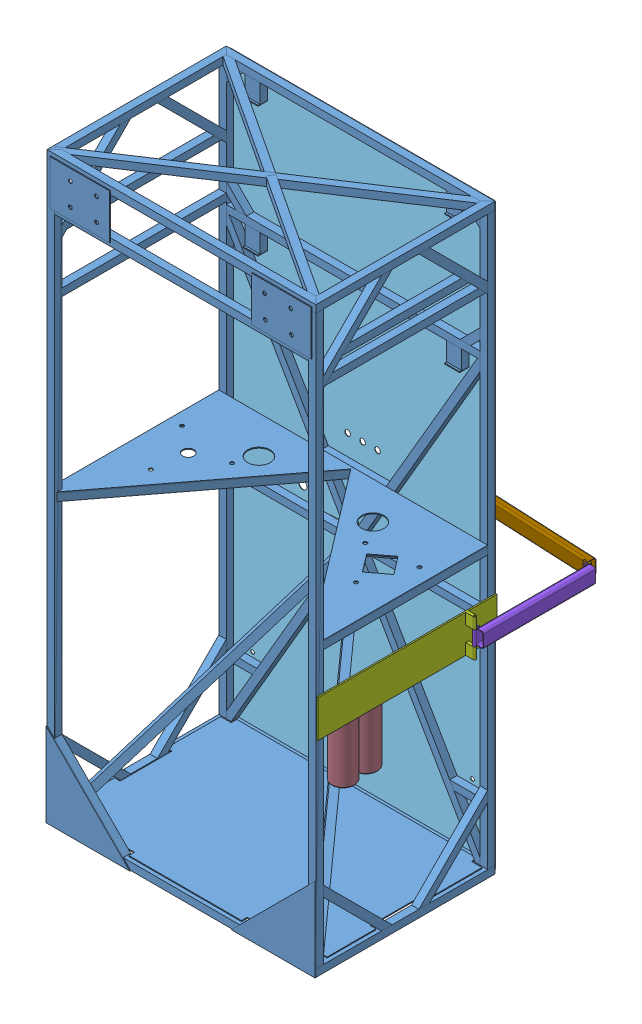
SolidWorks assembly Main Assembly, configuration Default. Lengths in mm.
Overall size (1333.5 2172.1 1083.06).
21 component instances, 13 part files, 25 mates.
Components (placement in the parent):
- test stand-1: test stand [Default<As Machined>] at origin size (1333.5 2172.1 876.3)
- Load cell and motor mount assembly final-1: Load cell and motor mount assembly final [Default] at (-8.9586 768.35 -389.2086) x (-1 0 0) z (0 -1 0) size (205.76 59.05 205.76)
  - Engine and Load Cell Mounting Plate3-1: Engine and Load Cell Mounting Plate3 [Default] at origin size (186.69 31.75 186.69)
  - Load Cell7-4: Load Cell7 [Default] at (0 -20.955 87.6411) x (0 0 -1) z (1 0 0) size (30.48 38.1 12.7)
  - load cell pin-2: load cell pin [Default] at (12.065 -7.62 77.4811) x (0 1 0) z (0 0 1) size (9.21 32.32 9.21)
  - load cell pin-5: load cell pin [Default] at (77.4811 -7.62 -12.065) x (0 1 0) z (1 0 0) size (9.21 32.32 9.21)
  - load cell pin-6: load cell pin [Default] at (-12.065 -7.62 -77.4811) x (0 1 0) z (0 0 -1) size (9.21 32.32 9.21)
  - load cell pin-7: load cell pin [Default] at (-77.4811 -7.62 12.065) x (0 1 0) z (-1 0 0) size (9.21 32.32 9.21)
  - Load Cell7-5: Load Cell7 [Default] at (87.6411 -20.955 0) x (-1 0 0) z (0 0 -1) size (30.48 38.1 12.7)
  - Load Cell7-6: Load Cell7 [Default] at (0 -20.955 -87.6411) x (0 0 1) z (-1 0 0) size (30.48 38.1 12.7)
  - Load Cell7-7: Load Cell7 [Default] at (-87.6411 -20.955 0) size (30.48 38.1 12.7)
- Blast Shield-1: Blast Shield [Default] at (6.35 996.95 -304.8) x (-1 0 0) z (0 0 -1) size (901.7 1968.5 1.59)
- Nozzle_Manifold-1: Nozzle_Manifold [Default] at (-8.9586 768.35 -549.5767) x (0.976633 0.214916 0) z (-0.214916 0.976633 0) size (138.44 174.52 138.44)
- Igniter Hinge Plate-1: Igniter Hinge Plate [Default] at (461.9625 762 -1.5875) x (0 0 1) z (-1 0 0) size (609.6 127 34.92)
- Igniter Arm 1st Section-1: Igniter Arm 1st Section [Default] at (500.0625 762 -400.05) x (0 1 0) z (0 0 -1) size (101.6 30.16 400.05)
- Igniter Arm 2nd Section-1: Igniter Arm 2nd Section [Default] at (267.5408 762 -618.3698) x (0 1 0) z (-0.998895 0 -0.047001) size (50.8 30.16 441.32)
- Igniter Torch-1: Igniter Torch [Default] at (-2.6983 761.9789 -554.7283) x (-0.086802 0.024341 -0.995928) z (0.179155 0.983785 0.00843) size (151.95 26.31 21.84)
- Igniter Torch Attatchment Bracket-1: Igniter Torch Attatchment Bracket [Default] at (5.3734 762 -619.6442) x (0.047001 0 -0.998895) z (0.998895 0 0.047001) size (12.7 38.1 71.44)
- Igniter Torch Attatchment Bracket Clamp-1: Igniter Torch Attatchment Bracket Clamp [Default] at (-4.8698 762 -620.1262) x (0.047001 0 -0.998895) z (0.998895 0 0.047001) size (12.7 38.1 15.88)
- FuelOxy Bottle-1: FuelOxy Bottle [Default] at (418.864 501.4728 95.8553) size (76.2 269.24 76.2)
- FuelOxy Bottle-2: FuelOxy Bottle [Default] at (418.3385 498.7814 173.287) size (76.2 269.24 76.2)
Mates (geometry in assembly coordinates):
- Coincident1: coincident: plane of test stand-1 through (457.2 1981.2 -304.8) normal (0 0 -1); plane of Blast Shield-1 through (6.35 996.95 -304.8) normal (0 0 1)
- Coincident2: coincident: plane of test stand-1 through (-444.5 1981.2 -279.4) normal (0 1 0); plane of Blast Shield-1 through (-444.5 1981.2 -306.3875) normal (0 1 0)
- Coincident3: coincident: plane of test stand-1 through (457.2 1981.2 -304.8) normal (1 0 0); plane of Blast Shield-1 through (457.2 1981.2 -306.3875) normal (1 0 0)
- Coincident4: coincident: plane of Load cell and motor mount assembly final-1/Engine and Load Cell Mounting Plate3-1 through (-8.9586 768.35 -397.4636) normal (0 0 -1); plane of Nozzle_Manifold-1 through (-76.069 753.5818 -397.4636) normal (0 0 1)
- Concentric1: concentric: cylinder of Load cell and motor mount assembly final-1/Engine and Load Cell Mounting Plate3-1 through (-8.9586 768.35 -397.4636) axis (0 0 -1) radius 81.915; cylinder of Nozzle_Manifold-1 through (-8.9586 768.35 -397.4636) axis (0 0 1) radius 68.7161
- Width1: width: plane of Load cell and motor mount assembly final-1/Load Cell7-6 through (-2.6086 871.2311 -387.3036) normal (0 1 0); plane of Load cell and motor mount assembly final-1/Load Cell7-4 through (-15.3086 665.4689 -387.3036) normal (0 -1 0); plane of Blast Shield-1 through (15.875 877.57 -306.3875) normal (0 -1 0); plane of Blast Shield-1 through (-3.175 659.13 -306.3875) normal (0 1 0)
- Parallel1: parallel: plane of Load cell and motor mount assembly final-1/Engine and Load Cell Mounting Plate3-1 through (-8.9586 768.35 -389.2086) normal (0 0 1); plane of Blast Shield-1 through (6.35 996.95 -306.3875) normal (0 0 -1)
- Coincident7: coincident: plane of Blast Shield-1 through (6.35 996.95 -306.3875) normal (0 0 -1); plane of Igniter Hinge Plate-1 through (457.2 698.5 -306.3875) normal (0 0 -1)
- Coincident8: coincident: plane of test stand-1 through (457.2 1981.2 -304.8) normal (1 0 0); plane of Igniter Hinge Plate-1 through (457.2 762 -1.5875) normal (-1 0 0)
- Concentric2: concentric: cylinder of Igniter Hinge Plate-1 through (487.3625 825.5 -204.7875) axis (0 -1 0) radius 3.175; cylinder of Igniter Arm 1st Section-1 through (487.3625 812.8 -204.7875) axis (0 -1 0) radius 3.175
- Coincident9: coincident: plane of Igniter Hinge Plate-1 through (461.9625 787.4 -306.3875) normal (0 -1 0); plane of Igniter Arm 1st Section-1 through (487.3625 787.4 -204.7875) normal (0 1 0)
- Distance1: distance = 127 mm: plane of test stand-1 through (457.2 952.5 -292.1) normal (0 -1 0); plane of Igniter Hinge Plate-1 through (457.2 825.5 -306.3875) normal (0 1 0)
- Concentric3: concentric: cylinder of Igniter Arm 1st Section-1 through (487.3625 711.2 -595.3125) axis (0 1 0) radius 3.175; cylinder of Igniter Arm 2nd Section-1 through (487.3625 781.05 -595.3125) axis (0 -1 0) radius 3.175
- Coincident11: coincident: plane of Igniter Arm 1st Section-1 through (512.7625 771.525 -590.55) normal (0 1 0); plane of Igniter Arm 2nd Section-1 through (483.7991 771.525 -620.9083) normal (0 -1 0)
- Distance2: distance = 25.4 mm: plane of Igniter Torch Attatchment Bracket-1 through (77.3289 742.95 -628.9726) normal (0.998895 0 0.047001); plane of Igniter Arm 2nd Section-1 through (51.5809 742.95 -622.1742) normal (-0.998895 0 -0.047001)
- Parallel2: parallel: plane of Igniter Hinge Plate-1 through (461.9625 762 -1.5875) normal (1 0 0); plane of Igniter Arm 1st Section-1 through (487.3625 742.95 -590.55) normal (-1 0 0)
- Parallel4: parallel: plane of Igniter Torch Attatchment Bracket-1 through (5.9703 781.05 -632.3302) normal (-0.998895 0 -0.047001); plane of Igniter Torch Attatchment Bracket Clamp-1 through (-4.2729 781.05 -632.8122) normal (0.998895 0 0.047001)
- Coincident18: coincident: plane of Igniter Torch Attatchment Bracket-1 through (5.9703 762 -632.3302) normal (0.047001 0 -0.998895); plane of Igniter Torch Attatchment Bracket Clamp-1 through (-4.2729 762 -632.8122) normal (0.047001 0 -0.998895)
- Tangent1: tangent: cylinder of Igniter Torch-1 through (0.2518 762 -619.8852) axis (-0.047001 0 0.998895) radius 10.922; plane of Igniter Torch Attatchment Bracket-1 through (5.9703 751.6812 -632.3302) normal (-0.706325 0.707107 -0.033235)
- Tangent2: tangent: cylinder of Igniter Torch-1 through (0.2518 762 -619.8852) axis (-0.047001 0 0.998895) radius 10.922; plane of Igniter Torch Attatchment Bracket-1 through (16.2777 762 -631.8452) normal (-0.706325 -0.707107 -0.033235)
- Tangent3: tangent: cylinder of Igniter Torch-1 through (0.2518 762 -619.8852) axis (-0.047001 0 0.998895) radius 10.922; plane of Igniter Torch Attatchment Bracket Clamp-1 through (-4.2729 772.3188 -632.8122) normal (0.706325 -0.707107 0.033235)
- Tangent4: tangent: cylinder of Igniter Torch-1 through (0.2518 762 -619.8852) axis (-0.047001 0 0.998895) radius 10.922; plane of Igniter Torch Attatchment Bracket Clamp-1 through (-14.5802 762 -633.2971) normal (0.706325 0.707107 0.033235)
- Coincident19: coincident: plane of Igniter Torch-1 through (10.9848 760.0411 -619.3802) normal (-0.047001 0 0.998895); plane of Igniter Torch Attatchment Bracket-1 through (5.3734 762 -619.6442) normal (-0.047001 0 0.998895)
- Width2: width: plane of Igniter Torch Attatchment Bracket-1 through (5.9703 742.95 -632.3302) normal (0 -1 0); plane of Igniter Torch Attatchment Bracket-1 through (77.3289 781.05 -628.9726) normal (0 1 0); plane of Igniter Arm 2nd Section-1 through (51.5809 787.4 -622.1742) normal (0 1 0); plane of Igniter Arm 2nd Section-1 through (51.5809 736.6 -622.1742) normal (0 -1 0)
- Coincident20: coincident: plane of Igniter Arm 2nd Section-1 through (51.3601 742.95 -617.4804) normal (0.047001 0 -0.998895); plane of Igniter Torch Attatchment Bracket-1 through (5.3734 762 -619.6442) normal (-0.047001 0 0.998895)
